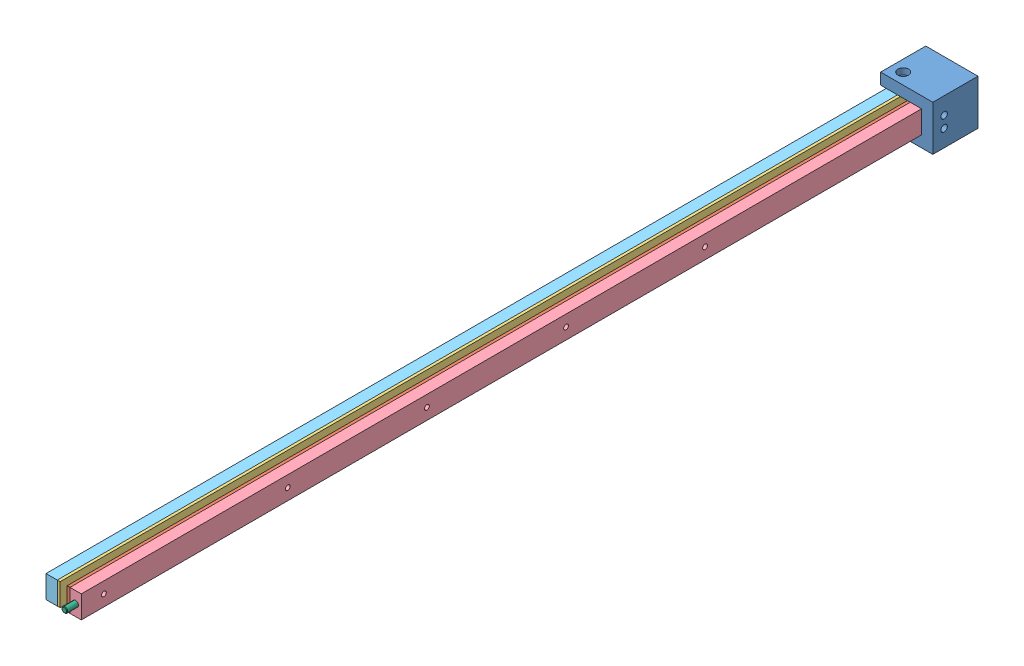
SolidWorks assembly clamp_assembly, configuration Default. Lengths in mm.
Overall size (29.37 25.4 504.19).
6 component instances, 6 part files, 13 mates.
Components (placement in the parent):
- KLMM006-1: KLMM006 [Default] at (17.0157 18.2813 34.9504) size (29.37 25.4 25.4)
- KLMM007-1: KLMM007 [Default] at (32.097 24.6313 47.6504) size (1.59 12.7 485.14)
- KLMM008-1: KLMM008 [Default] at (26.5407 24.6313 47.6504) size (1.59 12.7 485.14)
- KLMM003-1: KLMM003 [Default] at (33.6845 24.6313 47.6504) size (6.35 12.7 485.14)
- KLMM004-1: KLMM004 [Default] at (20.1907 24.6313 47.6504) size (6.35 12.7 485.14)
- 1_8x1_2_dowel-1: 1_8x1_2_dowel [90145A471] at (36.8595 30.9813 532.7904) x (0 0 -1) z (0.982234 -0.187658 0) size (12.7 3.17 3.17)
Mates (geometry in assembly coordinates):
- Coincident1: coincident anti-aligned: plane of KLMM006-1 through (40.0345 37.3313 44.4754) normal (-1 0 0); plane of KLMM003-1 through (40.0345 24.6313 532.7904) normal (1 0 0)
- Concentric1: concentric aligned: circle of KLMM006-1; circle of KLMM003-1
- Concentric2: concentric aligned: circle of KLMM006-1; circle of KLMM003-1
- Coincident2: coincident anti-aligned: plane of KLMM007-1 through (33.6845 24.6313 532.7904) normal (1 0 0); plane of KLMM003-1 through (33.6845 24.6313 532.7904) normal (-1 0 0)
- Concentric3: concentric aligned: circle of KLMM007-1; circle of KLMM003-1
- Concentric4: concentric aligned: circle of KLMM006-1; circle of KLMM007-1
- Coincident3: coincident anti-aligned: plane of KLMM008-1 through (26.5407 24.6313 532.7904) normal (-1 0 0); plane of KLMM004-1 through (26.5407 24.6313 532.7904) normal (1 0 0)
- Concentric5: concentric aligned: circle of KLMM008-1; circle of KLMM004-1
- Coincident6: coincident anti-aligned: plane of KLMM006-1 through (17.0157 24.6313 44.4754) normal (0 1 0); plane of KLMM004-1 through (20.1907 24.6313 532.7904) normal (0 -1 0)
- Concentric6: concentric aligned: circle of KLMM004-1; cylinder of KLMM006-1 through (23.3657 43.6813 54.0004) axis (0 1 0) radius 1.8288
- Parallel1: parallel aligned: line of KLMM007-1 through (32.097 37.3313 532.7904) axis (0 0 -1); line of KLMM008-1 through (28.1282 37.3313 532.7904) axis (0 0 -1)
- Concentric7: concentric anti-aligned: cylinder of KLMM003-1 through (36.8595 30.9813 526.4404) axis (0 0 1) radius 1.5875; cylinder of 1_8x1_2_dowel-1 through (36.8595 30.9813 539.1404) axis (0 0 -1) radius 1.5875
- Coincident7: coincident anti-aligned: plane of KLMM003-1 through (36.8595 30.9813 526.4404) normal (0 0 1); plane of 1_8x1_2_dowel-1 through (36.8595 30.9813 526.4404) normal (0 0 -1)
